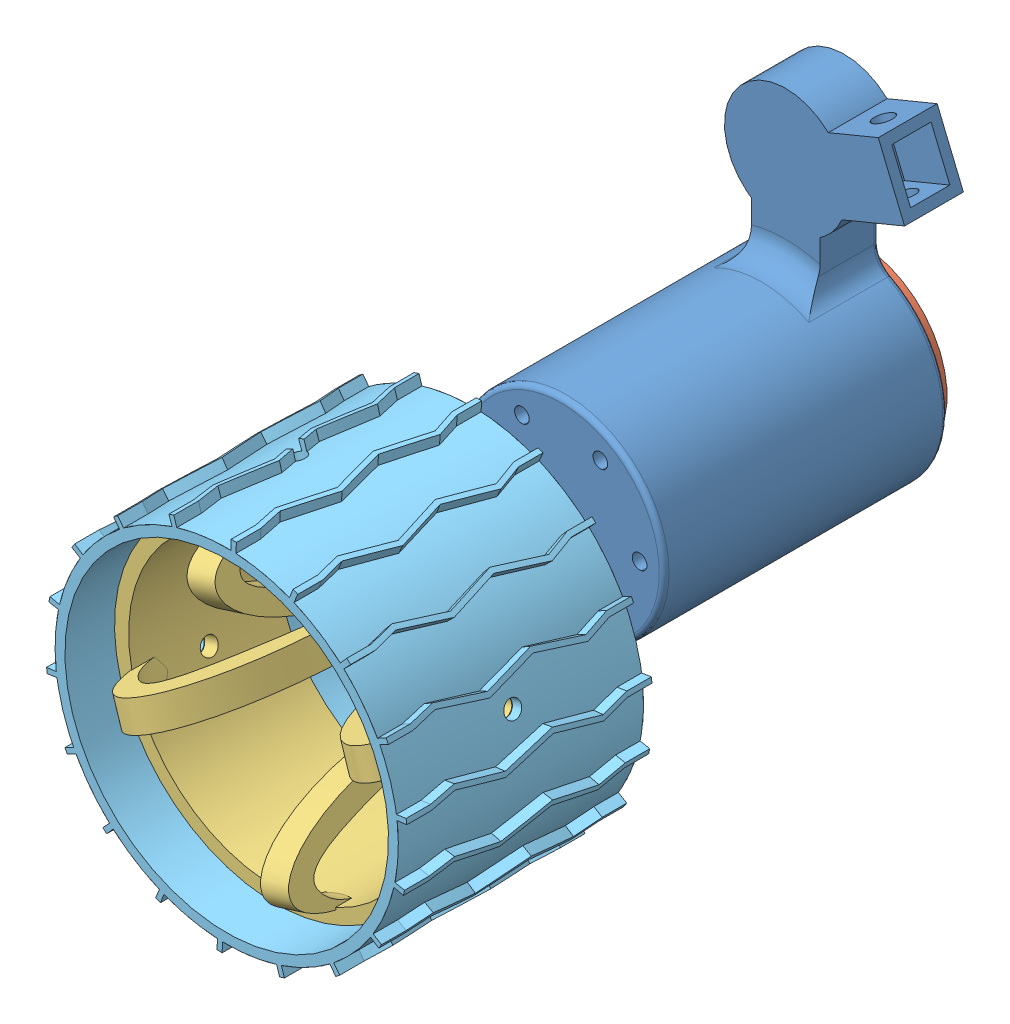
SolidWorks assembly Middle Wheel, configuration Default. Lengths in mm.
Overall size (92.57 106.34 128.8).
6 component instances, 5 part files, 2 mates.
Components (placement in the parent):
- A_H_Motor-1: A_H_Motor [Default] at (-41.8905 27.9503 -10.3557) size (45.23 74.39 57.8)
- Motor x Wheel Assembly-1: Motor x Wheel Assembly [Default] at (18.4664 -15.3532 60.2321) x (1 0 0) z (0 0 -1) size (92.57 92.9 128.8)
  - motor-1: motor [Default] at (-60.357 -3.1473 15.5878) size (37 37 78.8)
  - wheel inner-1: wheel inner [Default] at (-60.357 3.3527 -15.4122) x (0.952401 -0.304848 0) z (0.304848 0.952401 0) size (65.75 39.75 65.75)
  - wheel x motor connector test 2-1: wheel x motor connector test 2 [Default] at (-60.357 3.3527 9.5878) x (0.889009 0.457889 0) z (0 0 -1) size (25 25 25)
  - wheel outer-1: wheel outer [Default] at (-60.357 3.3527 -55.4122) x (-0.304848 -0.952401 0) z (0 0 1) size (74.01 73.51 50)
Mates (geometry in assembly coordinates):
- Coincident4: coincident anti-aligned: circle of A_H_Motor-1; circle of Motor x Wheel Assembly-1/motor-1
- Coincident5: coincident anti-aligned: circle of A_H_Motor-1; circle of Motor x Wheel Assembly-1/motor-1
